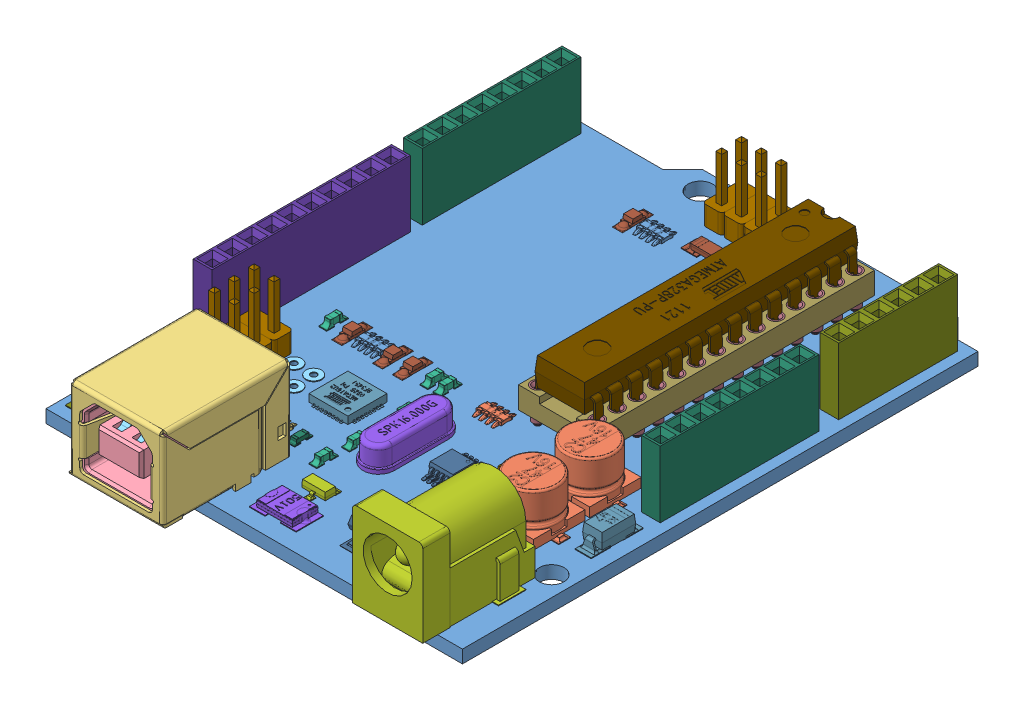
SolidWorks assembly arduino uno, configuration Default. Lengths in mm.
Overall size (53.34 15.25 74.97).
87 component instances, 35 part files, 133 mates.
Components (placement in the parent):
- unoboard blue-1: unoboard blue [Default] at origin size (53.34 1.65 68.58)
- 47uf CAP Dcase-1: 47uf CAP Dcase [Default] at (-9.4141 0 -18.4991) x (0 0 -1) z (1 0 0) size (6.6 5.81 8)
- USB type b-1: USB type b [Default] at (-38.02 0.43 6.35) size (14.34 15.2 16.54)
  - USB SHELL-1: USB SHELL [Default] at origin size (14.34 15.2 16.5)
  - USB core-1: USB core [Default] at origin size (11.3 10.68 15.75)
  - usb top contact-1: usb top contact [Default] at (1.25 6.09 -0.38) size (1 9.67 13.76)
  - usb btm contact-1: usb btm contact [Default] at (1.25 4.41 -0.38) size (1 6.84 11.76)
  - usb btm contact-2: usb btm contact [Default] at (-1.25 4.41 -0.38) size (1 6.84 11.76)
  - usb top contact-2: usb top contact [Default] at (-1.25 6.09 -0.38) size (1 9.67 13.76)
- power jack-1: power jack [Default] at (-7.675 0 1.905) size (11.2 15.2 15.9)
- 47uf CAP Dcase-2: 47uf CAP Dcase [Default] at (-9.4141 0 -25.7132) x (0 0 -1) z (1 0 0) size (6.6 5.81 8)
- crystal-1: crystal [Default] at (-26.162 0 -18.923) x (1 0 0) z (0 0 -1) size (4 5 11)
- 2pin_header__02-1: 2pin_header__02 [Default] at (-46.23 0 -15.75) size (5 11.75 2.54)
- nano - reg-1: nano - reg [Default] at (-17.399 0 -7.747) size (6.5 1.69 8.3)
- led-1: led [Default] at (-34.29 0 -27.94) x (0 0 1) z (-1 0 0) size (4 0.86 1.35)
- 2pin_header__02-2: 2pin_header__02 [Default] at (-30.43 0 -64.91) x (0 0 1) z (-1 0 0) size (5 11.75 2.54)
- dip28-1: dip28 [Default] at (-16.383 1.5 -46.355) x (0 0 -1) z (1 0 0) size (35.48 7.37 10.1)
  - dip28-1: dip28 [Default] at origin size (35.48 2.8 10.1)
  - dip socket pin-1: dip socket pin [Default] at (16.51 2.8 -3.81) size (1.7 7.37 1.7)
  - dip socket pin-2: dip socket pin [Default] at (16.51 2.8 3.81) size (1.7 7.37 1.7)
  - dip socket pin-3: dip socket pin [Default] at (13.97 2.8 -3.81) size (1.7 7.37 1.7)
  - dip socket pin-4: dip socket pin [Default] at (13.97 2.8 3.81) size (1.7 7.37 1.7)
  - dip socket pin-5: dip socket pin [Default] at (11.43 2.8 -3.81) size (1.7 7.37 1.7)
  - dip socket pin-6: dip socket pin [Default] at (11.43 2.8 3.81) size (1.7 7.37 1.7)
  - dip socket pin-7: dip socket pin [Default] at (8.89 2.8 -3.81) size (1.7 7.37 1.7)
  - dip socket pin-8: dip socket pin [Default] at (8.89 2.8 3.81) size (1.7 7.37 1.7)
  - dip socket pin-9: dip socket pin [Default] at (6.35 2.8 -3.81) size (1.7 7.37 1.7)
  - dip socket pin-10: dip socket pin [Default] at (6.35 2.8 3.81) size (1.7 7.37 1.7)
  - dip socket pin-11: dip socket pin [Default] at (3.81 2.8 -3.81) size (1.7 7.37 1.7)
  - dip socket pin-12: dip socket pin [Default] at (3.81 2.8 3.81) size (1.7 7.37 1.7)
  - dip socket pin-13: dip socket pin [Default] at (1.27 2.8 -3.81) size (1.7 7.37 1.7)
  - dip socket pin-14: dip socket pin [Default] at (1.27 2.8 3.81) size (1.7 7.37 1.7)
  - dip socket pin-15: dip socket pin [Default] at (-1.27 2.8 -3.81) size (1.7 7.37 1.7)
  - dip socket pin-16: dip socket pin [Default] at (-1.27 2.8 3.81) size (1.7 7.37 1.7)
  - dip socket pin-17: dip socket pin [Default] at (-3.81 2.8 -3.81) size (1.7 7.37 1.7)
  - dip socket pin-18: dip socket pin [Default] at (-3.81 2.8 3.81) size (1.7 7.37 1.7)
  - dip socket pin-19: dip socket pin [Default] at (-6.35 2.8 -3.81) size (1.7 7.37 1.7)
  - dip socket pin-20: dip socket pin [Default] at (-6.35 2.8 3.81) size (1.7 7.37 1.7)
  - dip socket pin-21: dip socket pin [Default] at (-8.89 2.8 -3.81) size (1.7 7.37 1.7)
  - dip socket pin-22: dip socket pin [Default] at (-8.89 2.8 3.81) size (1.7 7.37 1.7)
  - dip socket pin-23: dip socket pin [Default] at (-11.43 2.8 -3.81) size (1.7 7.37 1.7)
  - dip socket pin-24: dip socket pin [Default] at (-11.43 2.8 3.81) size (1.7 7.37 1.7)
  - dip socket pin-25: dip socket pin [Default] at (-13.97 2.8 -3.81) size (1.7 7.37 1.7)
  - dip socket pin-26: dip socket pin [Default] at (-13.97 2.8 3.81) size (1.7 7.37 1.7)
  - dip socket pin-27: dip socket pin [Default] at (-16.51 2.8 -3.81) size (1.7 7.37 1.7)
  - dip socket pin-28: dip socket pin [Default] at (-16.51 2.8 3.81) size (1.7 7.37 1.7)
- 2pin_header__02-3: 2pin_header__02 [Default] at (-27.89 0 -64.91) x (0 0 1) z (-1 0 0) size (5 11.75 2.54)
- 2pin_header__02-4: 2pin_header__02 [Default] at (-25.35 0 -64.91) x (0 0 1) z (-1 0 0) size (5 11.75 2.54)
- 2pin_header__02-5: 2pin_header__02 [Default] at (-46.23 0 -18.29) size (5 11.75 2.54)
- 2pin_header__02-6: 2pin_header__02 [Default] at (-46.23 0 -20.83) size (5 11.75 2.54)
- atmega16u2-1: atmega16u2 [Default] at (-34.671 0.06 -20) x (1 0 0) z (0 0 -1) size (5.5 1.01 5.5)
- led-2: led [Default] at (-36.83 0 -27.94) x (0 0 1) z (-1 0 0) size (4 0.86 1.35)
- led-3: led [Default] at (-42.037 0 -27.94) x (0 0 1) z (-1 0 0) size (4 0.86 1.35)
- led-4: led [Default] at (-36.576 0 -58.42) x (0 0 1) z (-1 0 0) size (4 0.86 1.35)
- 8 PORT HEADER-3: 8 PORT HEADER [Default] at (-50.8 0 -45.72) x (0 0 -1) z (1 0 0) size (20.32 10.51 2.41)
- 8 PORT HEADER-4: 8 PORT HEADER [Default] at (-2.54 0 -27.94) x (0 0 -1) z (1 0 0) size (20.32 10.51 2.41)
- 6 PORT HEADER-3: 6 PORT HEADER [Default] at (-2.54 0 -50.8) x (0 0 -1) z (1 0 0) size (15.24 10.51 2.41)
- 10 PORT HEADER-1: 10 PORT HEADER [Default] at (-50.8 0 -18.796) x (0 0 -1) z (1 0 0) size (25.4 10.51 2.41)
- ATMEL328P-1: ATMEL328P [Default] at (-16.383 4.3 -46.355) x (0 0 -1) z (1 0 0) size (35 7.27 7.87)
- 102 RESISTOR PACK-1: 102 RESISTOR PACK [Default] at (-33.782 0 -58.42) size (3.2 0.46 3)
- 102 RESISTOR PACK-2: 102 RESISTOR PACK [Default] at (-39.37 0 -27.94) size (3.2 0.46 3)
- 103 RESISTOR PACK-3: 103 RESISTOR PACK [Default] at (-23.876 0 -27.94) size (3.2 0.46 3)
- 220 RESISTOR PACK-1: 220 RESISTOR PACK [Default] at (-36.83 0 -12.827) size (3.2 0.46 3)
- 16mhz crystal - measured-1: 16mhz crystal - measured [Default] at (-24.892 0 -41.275) x (0 0 -1) z (1 0 0) size (3.4 0.8 2)
- PADS001-1: PADS001 [Default] at (-39.878 0.1 -18.288) x (-1 0 0) z (0 0 1) size (4.54 0.1 4.54)
- 603 cap on pad-1: 603 cap on pad [Default] at (-44.45 0 -27.94) x (0 0 -1) z (1 0 0) size (2.76 0.9 1.12)
- ssot3-1: ssot3 [Default] at (-26.5 0 -8.128) x (-1 0 0) z (0 0 -1) size (3 1.13 3.09)
- mf-msmf050-2-1: mf-msmf050-2 [Default] at (-26.5 0 -4.064) size (5.77 1.02 3.72)
- 603 cap on pad-2: 603 cap on pad [Default] at (-29.845 0 -27.94) x (0 0 -1) z (1 0 0) size (2.76 0.9 1.12)
- 603 cap on pad-3: 603 cap on pad [Default] at (-31.496 0 -27.94) x (0 0 -1) z (1 0 0) size (2.76 0.9 1.12)
- lmv358-1: lmv358 [Default] at (-15.24 0 -21.971) x (0 0 -1) z (1 0 0) size (3.7 1.4 2.9)
- 603 cap on pad-4: 603 cap on pad [Default] at (-15.24 0 -18.415) size (2.76 0.9 1.12)
- 603 cap on pad-5: 603 cap on pad [Default] at (-29.845 0 -12.065) x (0 0 1) z (-1 0 0) size (2.76 0.9 1.12)
- 603 cap on pad-6: 603 cap on pad [Default] at (-29.591 0 -22.352) x (0 0 1) z (-1 0 0) size (2.76 0.9 1.12)
- 603 cap on pad-7: 603 cap on pad [Default] at (-29.591 0 -16.002) x (0 0 1) z (-1 0 0) size (2.76 0.9 1.12)
- 603 cap on pad-8: 603 cap on pad [Default] at (-41.91 0 -12.7) x (0 0 1) z (-1 0 0) size (2.76 0.9 1.12)
- lp2985dgkr-1: lp2985dgkr [Default] at (-20.32 0 -19.05) x (0 0 -1) z (1 0 0) size (5.85 1.1 3)
- cd1206 diode-1: cd1206 diode [Default] at (-27.94 0 -59.436) x (0 0 -1) z (1 0 0) size (2.07 0.96 5)
- cd1206 diode-2: cd1206 diode [Default] at (-46.228 0 -13.081) x (0 0 1) z (-1 0 0) size (2.07 0.96 5)
- 603 resistor-1: 603 resistor [Default] at (-29.591 0 -19.05) x (0 0 1) z (-1 0 0) size (2.36 0.61 1.03)
- blm21-1: blm21 [Default] at (-45.085 0 -7.62) x (0 0 -1) z (1 0 0) size (2.76 0.95 1.32)
- m7 diode-1: m7 diode [Default] at (-2.794 0 -21.59) x (0 0 -1) z (1 0 0) size (6.66 2.35 2.5)
- MLC0603-1: MLC0603 [Default] at (-33.655 0 -12.827) x (0 0 -1) z (1 0 0) size (2.36 0.6 1.03)
- MLC0603-2: MLC0603 [Default] at (-39.37 0 -12.827) x (0 0 -1) z (1 0 0) size (2.36 0.6 1.03)
- RESET BUTTON-1: RESET BUTTON [Default] at (-49.403 0 -6.35) size (6.2 3.1 9.6)
  - RESET CORE-1: RESET CORE [Default] at (0 0.1 0) x (-1 0 0) z (0 0 -1) size (6.2 3.1 9.6)
  - RESET-1: RESET [Default] at (0 0.1 0) x (0 0 1) z (-1 0 0) size (7.3 2 6.2)
Mates (geometry in assembly coordinates):
- Distance1: distance = 1.905 mm aligned: plane of power jack-1 through (-7.675 0 1.905) normal (0 0 1); plane of unoboard blue-1 through (0 0 0) normal (0 0 1)
- Coincident2: coincident aligned: plane of unoboard blue-1 through (0 0 0) normal (0 1 0); plane of power jack-1 through (-7.675 0 1.905) normal (0 1 0)
- Coincident3: coincident anti-aligned: plane of unoboard blue-1 through (0 0 0) normal (0 1 0); plane of USB type b-1/USB core-1 through (-38.02 0 6.35) normal (0 -1 0)
- Distance2: distance = 6.35 mm aligned: plane of USB type b-1/USB SHELL-1 through (-38.02 0.43 6.35) normal (0 0 1); plane of unoboard blue-1 through (0 0 0) normal (0 0 1)
- Coincident5: coincident aligned: plane of unoboard blue-1 through (0 0 0) normal (0 1 0); plane of 47uf CAP Dcase-1 through (-9.4141 0 -18.4991) normal (0 1 0)
- Parallel1: parallel anti-aligned: plane of unoboard blue-1 through (0 0 0) normal (0 0 1); plane of 47uf CAP Dcase-1 through (-9.4141 0 -18.4991) normal (0 0 -1)
- Coincident7: coincident aligned: plane of 47uf CAP Dcase-1 through (-6.1141 1.5 -15.1991) normal (1 0 0); plane of 47uf CAP Dcase-2 through (-6.1141 1.5 -22.4132) normal (1 0 0)
- Coincident8: coincident anti-aligned: plane of unoboard blue-1 through (0 0 0) normal (0 1 0); plane of 47uf CAP Dcase-2 through (-8.1891 0 -25.7132) normal (0 -1 0)
- Distance3: distance = 3.175 mm aligned: plane of power jack-1 through (-3.175 10.5 -1.595) normal (1 0 0); plane of unoboard blue-1 through (0 -1.65 0) normal (1 0 0)
- Distance4: distance = 32 mm aligned: plane of USB type b-1/USB SHELL-1 through (-32 0.43 6.35) normal (1 0 0); plane of unoboard blue-1 through (0 -1.65 0) normal (1 0 0)
- Coincident11: coincident anti-aligned: plane of unoboard blue-1 through (0 0 0) normal (0 1 0); plane of crystal-1 through (-26.162 0 -22.423) normal (0 -1 0)
- Concentric1: concentric aligned: cylinder of unoboard blue-1 through (-26.162 -10 -16.383) axis (0 1 0) radius 0.5; cylinder of crystal-1 through (-26.162 -2 -16.383) axis (0 1 0) radius 0.4
- Concentric2: concentric aligned: cylinder of unoboard blue-1 through (-26.162 -10 -21.463) axis (0 1 0) radius 0.5; cylinder of crystal-1 through (-26.162 -2 -21.463) axis (0 1 0) radius 0.4
- Coincident12: coincident anti-aligned: plane of unoboard blue-1 through (0 0 0) normal (0 1 0); plane of 2pin_header__02-1 through (-44.23 0 -14.98) normal (0 -1 0)
- Distance5: distance = 15.75 mm aligned: plane of 2pin_header__02-1 through (-46.23 0 -15.75) normal (0 0 1); plane of assembly through (0 0 0) normal (0 0 1)
- Distance6: distance = 46.23 mm aligned: plane of 2pin_header__02-1 through (-46.23 0 -15.75) normal (1 0 0); plane of assembly through (0 0 0) normal (1 0 0)
- Coincident15: coincident anti-aligned: plane of unoboard blue-1 through (0 0 0) normal (0 1 0); plane of 2pin_header__02-2 through (-31.2 0 -62.91) normal (0 -1 0)
- Distance7: distance = 64.91 mm aligned: plane of 2pin_header__02-2 through (-30.43 0 -64.91) normal (0 0 1); plane of assembly through (0 0 0) normal (0 0 1)
- Distance8: distance = 30.43 mm anti-aligned: plane of 2pin_header__02-2 through (-30.43 0 -64.91) normal (-1 0 0); plane of assembly through (0 0 0) normal (1 0 0)
- Coincident19: coincident anti-aligned: plane of unoboard blue-1 through (0 0 0) normal (0 1 0); plane of nano - reg-1 through (-17.399 0 -7.747) normal (0 -1 0)
- Concentric3: concentric aligned: cylinder of unoboard blue-1 through (-20.193 -10 -62.865) axis (0 1 0) radius 0.4; cylinder of dip28-1/dip socket pin-1 through (-20.193 33.2926 -62.865) axis (0 1 0) radius 0.25
- Concentric4: concentric aligned: cylinder of unoboard blue-1 through (-12.573 -10 -29.845) axis (0 1 0) radius 0.4; cylinder of dip28-1/dip socket pin-28 through (-12.573 33.2926 -29.845) axis (0 1 0) radius 0.25
- Distance9: distance = 1.5 mm anti-aligned: plane of dip28-1/dip28-1 through (-11.333 1.5 -64.095) normal (0 -1 0); plane of unoboard blue-1 through (0 0 0) normal (0 1 0)
- Coincident21: coincident anti-aligned: plane of unoboard blue-1 through (0 0 0) normal (0 1 0); plane of atmega16u2-1 through (-34.671 0 -20) normal (0 -1 0)
- Distance10: distance = 20 mm anti-aligned: plane of atmega16u2-1 through (-34.671 0.06 -20) normal (0 0 -1); plane of unoboard blue-1 through (0 0 0) normal (0 0 1)
- Distance11: distance = 34.671 mm aligned: plane of atmega16u2-1 through (-34.671 0.06 -20) normal (1 0 0); plane of unoboard blue-1 through (0 0 0) normal (1 0 0)
- Coincident25: coincident anti-aligned: plane of unoboard blue-1 through (0 0 0) normal (0 1 0); plane of led-1 through (-34.29 0 -28.94) normal (0 -1 0)
- Distance12: distance = 34.29 mm anti-aligned: plane of led-1 through (-34.29 0 -27.94) normal (-1 0 0); plane of unoboard blue-1 through (0 0 0) normal (1 0 0)
- Distance13: distance = 27.94 mm aligned: plane of led-1 through (-34.29 0 -27.94) normal (0 0 1); plane of unoboard blue-1 through (0 0 0) normal (0 0 1)
- Coincident28: coincident aligned: plane of led-2 through (-36.83 0 -28.94) normal (0 -1 0); plane of led-3 through (-42.037 0 -28.94) normal (0 -1 0)
- Coincident29: coincident aligned: plane of led-1 through (-34.29 0 -27.94) normal (0 0 1); plane of led-2 through (-36.83 0 -27.94) normal (0 0 1)
- Coincident30: coincident aligned: plane of led-1 through (-34.29 0 -27.94) normal (0 0 1); plane of led-3 through (-42.037 0 -27.94) normal (0 0 1)
- Distance14: distance = 2.54 mm aligned: plane of led-2 through (-36.83 0 -27.94) normal (-1 0 0); plane of led-1 through (-34.29 0 -27.94) normal (-1 0 0)
- Coincident32: coincident anti-aligned: plane of unoboard blue-1 through (0 0 0) normal (0 1 0); plane of led-2 through (-36.83 0 -28.94) normal (0 -1 0)
- Distance15: distance = 42.037 mm anti-aligned: plane of led-3 through (-42.037 0 -27.94) normal (-1 0 0); plane of unoboard blue-1 through (0 0 0) normal (1 0 0)
- Coincident34: coincident anti-aligned: plane of unoboard blue-1 through (0 0 0) normal (0 1 0); plane of led-4 through (-36.576 0 -59.42) normal (0 -1 0)
- Distance16: distance = 36.576 mm anti-aligned: plane of led-4 through (-36.576 0 -58.42) normal (-1 0 0); plane of unoboard blue-1 through (0 0 0) normal (1 0 0)
- Distance17: distance = 58.42 mm aligned: plane of led-4 through (-36.576 0 -58.42) normal (0 0 1); plane of unoboard blue-1 through (0 0 0) normal (0 0 1)
- Coincident37: coincident aligned: plane of unoboard blue-1 through (0 0 0) normal (0 1 0); plane of 8 PORT HEADER-4 through (-2.54 0 -27.94) normal (0 1 0)
- Coincident38: coincident aligned: plane of unoboard blue-1 through (0 0 0) normal (0 1 0); plane of 8 PORT HEADER-3 through (-50.8 0 -45.72) normal (0 1 0)
- Parallel2: parallel aligned: plane of unoboard blue-1 through (0 0 0) normal (1 0 0); plane of 8 PORT HEADER-4 through (-2.54 0 -27.94) normal (1 0 0)
- Parallel3: parallel aligned: plane of unoboard blue-1 through (0 0 0) normal (1 0 0); plane of 8 PORT HEADER-3 through (-50.8 0 -45.72) normal (1 0 0)
- Concentric5: concentric aligned: cylinder of unoboard blue-1 through (-2.54 -1.65 -27.94) axis (0 1 0) radius 0.4; line of 8 PORT HEADER-4 through (-2.54 -2.5255 -27.94) axis (0 1 0)
- Concentric6: concentric aligned: cylinder of unoboard blue-1 through (-50.8 -1.65 -45.72) axis (0 1 0) radius 0.4; line of 8 PORT HEADER-3 through (-50.8 -2.5255 -45.72) axis (0 1 0)
- Coincident43: coincident aligned: plane of unoboard blue-1 through (0 0 0) normal (0 1 0); plane of 10 PORT HEADER-1 through (-50.8 0 -18.796) normal (0 1 0)
- Coincident44: coincident aligned: plane of unoboard blue-1 through (0 0 0) normal (0 1 0); plane of 6 PORT HEADER-3 through (-2.54 0 -50.8) normal (0 1 0)
- Parallel4: parallel aligned: plane of unoboard blue-1 through (0 0 0) normal (1 0 0); plane of 6 PORT HEADER-3 through (-2.54 0 -50.8) normal (1 0 0)
- Parallel5: parallel aligned: plane of unoboard blue-1 through (0 0 0) normal (1 0 0); plane of 10 PORT HEADER-1 through (-50.8 0 -18.796) normal (1 0 0)
- Concentric7: concentric aligned: cylinder of unoboard blue-1 through (-50.8 -1.65 -18.796) axis (0 1 0) radius 0.4; line of 10 PORT HEADER-1 through (-50.8 -2.5255 -18.796) axis (0 1 0)
- Concentric9: concentric aligned: cylinder of unoboard blue-1 through (-2.54 -1.65 -50.8) axis (0 1 0) radius 0.4; line of 6 PORT HEADER-3 through (-2.54 -2.5255 -50.8) axis (0 1 0)
- Coincident50: coincident aligned: plane of dip28-1/dip28-1 through (-16.383 1.5 -46.355) normal (0 0 -1); plane of ATMEL328P-1 through (-16.383 4.3 -46.355) normal (0 0 -1)
- Coincident51: coincident aligned: plane of dip28-1 through (-16.383 1.5 -46.355) normal (1 0 0); plane of ATMEL328P-1 through (-16.383 4.3 -46.355) normal (1 0 0)
- Coincident52: coincident aligned: plane of dip28-1/dip28-1 through (-11.333 4.3 -64.095) normal (0 1 0); plane of ATMEL328P-1 through (-16.383 4.3 -46.355) normal (0 1 0)
- Distance18: distance = 7.747 mm: plane of nano - reg-1 through (-17.399 0 -7.747) normal (0 0 1); line of unoboard blue-1 through (0 53.34 -53.34) axis (0 0 1)
- Distance19: distance = 17.399 mm aligned: plane of nano - reg-1 through (-17.399 0 -7.747) normal (1 0 0); plane of unoboard blue-1 through (0 0 0) normal (1 0 0)
- Coincident55: coincident anti-aligned: plane of unoboard blue-1 through (0 0 0) normal (0 1 0); plane of 102 RESISTOR PACK-1 through (-33.982 0 -59.12) normal (0 -1 0)
- Distance20: distance = 33.782 mm aligned: plane of 102 RESISTOR PACK-1 through (-33.782 0 -58.42) normal (1 0 0); plane of unoboard blue-1 through (0 0 0) normal (1 0 0)
- Distance21: distance = 58.42 mm aligned: plane of 102 RESISTOR PACK-1 through (-33.782 0 -58.42) normal (0 0 1); plane of unoboard blue-1 through (0 0 0) normal (0 0 1)
- Coincident58: coincident aligned: plane of 102 RESISTOR PACK-2 through (-39.37 0 -27.94) normal (0 1 0); plane of 103 RESISTOR PACK-3 through (-23.876 0 -27.94) normal (0 1 0)
- Coincident59: coincident aligned: plane of unoboard blue-1 through (0 0 0) normal (0 1 0); plane of 103 RESISTOR PACK-3 through (-23.876 0 -27.94) normal (0 1 0)
- Coincident60: coincident aligned: plane of 102 RESISTOR PACK-2 through (-39.37 0 -27.94) normal (0 0 1); plane of 103 RESISTOR PACK-3 through (-23.876 0 -27.94) normal (0 0 1)
- Distance22: distance = 23.876 mm aligned: plane of 103 RESISTOR PACK-3 through (-23.876 0 -27.94) normal (1 0 0); plane of unoboard blue-1 through (0 0 0) normal (1 0 0)
- Distance23: distance = 39.37 mm aligned: plane of 102 RESISTOR PACK-2 through (-39.37 0 -27.94) normal (1 0 0); plane of unoboard blue-1 through (0 0 0) normal (1 0 0)
- Distance24: distance = 27.94 mm aligned: plane of 102 RESISTOR PACK-2 through (-39.37 0 -27.94) normal (0 0 1); plane of unoboard blue-1 through (0 0 0) normal (0 0 1)
- Distance25: distance = 12.827 mm aligned: plane of 220 RESISTOR PACK-1 through (-36.83 0 -12.827) normal (0 0 1); plane of unoboard blue-1 through (0 0 0) normal (0 0 1)
- Distance26: distance = 36.83 mm aligned: plane of 220 RESISTOR PACK-1 through (-36.83 0 -12.827) normal (1 0 0); plane of unoboard blue-1 through (0 0 0) normal (1 0 0)
- Coincident66: coincident aligned: plane of unoboard blue-1 through (0 0 0) normal (0 1 0); plane of 220 RESISTOR PACK-1 through (-36.83 0 -12.827) normal (0 1 0)
- Coincident67: coincident anti-aligned: plane of unoboard blue-1 through (0 0 0) normal (0 1 0); plane of 16mhz crystal - measured-1 through (-24.892 0 -41.275) normal (0 -1 0)
- Distance27: distance = 41.275 mm anti-aligned: plane of 16mhz crystal - measured-1 through (-24.892 0 -41.275) normal (0 0 -1); plane of unoboard blue-1 through (0 0 0) normal (0 0 1)
- Distance28: distance = 24.892 mm aligned: plane of 16mhz crystal - measured-1 through (-24.892 0 -41.275) normal (1 0 0); plane of unoboard blue-1 through (0 0 0) normal (1 0 0)
- Coincident70: coincident anti-aligned: plane of unoboard blue-1 through (0 0 0) normal (0 1 0); plane of PADS001-1 through (-42.418 0 -18.288) normal (0 -1 0)
- Distance29: distance = 18.288 mm aligned: plane of PADS001-1 through (-39.878 0.1 -18.288) normal (0 0 1); plane of unoboard blue-1 through (0 0 0) normal (0 0 1)
- Distance30: distance = 39.878 mm anti-aligned: plane of PADS001-1 through (-39.878 0.1 -18.288) normal (-1 0 0); plane of unoboard blue-1 through (0 0 0) normal (1 0 0)
- Distance31: distance = 4.064 mm aligned: plane of mf-msmf050-2-1 through (-26.5 0 -4.064) normal (0 0 1); plane of unoboard blue-1 through (0 0 0) normal (0 0 1)
- Distance32: distance = 26.5 mm aligned: plane of mf-msmf050-2-1 through (-26.5 0 -4.064) normal (1 0 0); plane of unoboard blue-1 through (0 0 0) normal (1 0 0)
- Coincident72: coincident aligned: plane of unoboard blue-1 through (0 0 0) normal (0 1 0); plane of mf-msmf050-2-1 through (-26.5 0 -4.064) normal (0 1 0)
- Distance33: distance = 8.128 mm anti-aligned: plane of unoboard blue-1 through (0 0 0) normal (0 0 1); plane of ssot3-1 through (-26.5 0 -8.128) normal (0 0 -1)
- Coincident74: coincident anti-aligned: plane of ssot3-1 through (-26.5 0 -8.128) normal (-1 0 0); plane of mf-msmf050-2-1 through (-26.5 0 -4.064) normal (1 0 0)
- Coincident75: coincident aligned: plane of unoboard blue-1 through (0 0 0) normal (0 1 0); plane of ssot3-1 through (-26.5 0 -8.128) normal (0 1 0)
- Coincident76: coincident anti-aligned: plane of led-1 through (-34.29 0 -27.94) normal (0 0 1); plane of 603 cap on pad-1 through (-44.45 0 -27.94) normal (0 0 -1)
- Coincident77: coincident aligned: plane of unoboard blue-1 through (0 0 0) normal (0 1 0); plane of 603 cap on pad-1 through (-44.45 0 -27.94) normal (0 1 0)
- Distance34: distance = 44.45 mm aligned: plane of 603 cap on pad-1 through (-44.45 0 -27.94) normal (1 0 0); plane of unoboard blue-1 through (0 0 0) normal (1 0 0)
- Coincident79: coincident aligned: plane of 603 cap on pad-2 through (-29.845 0 -27.94) normal (0 1 0); plane of 603 cap on pad-3 through (-31.496 0 -27.94) normal (0 1 0)
- Coincident80: coincident aligned: plane of 603 cap on pad-2 through (-29.845 0 -27.94) normal (0 0 -1); plane of 603 cap on pad-3 through (-31.496 0 -27.94) normal (0 0 -1)
- Coincident81: coincident aligned: plane of unoboard blue-1 through (0 0 0) normal (0 1 0); plane of 603 cap on pad-2 through (-29.845 0 -27.94) normal (0 1 0)
- Coincident82: coincident aligned: plane of 603 cap on pad-1 through (-44.45 0 -27.94) normal (0 0 -1); plane of 603 cap on pad-2 through (-29.845 0 -27.94) normal (0 0 -1)
- Distance36: distance = 29.845 mm aligned: plane of 603 cap on pad-2 through (-29.845 0 -27.94) normal (1 0 0); plane of unoboard blue-1 through (0 0 0) normal (1 0 0)
- Distance37: distance = 31.496 mm aligned: plane of 603 cap on pad-3 through (-31.496 0 -27.94) normal (1 0 0); plane of unoboard blue-1 through (0 0 0) normal (1 0 0)
- Distance38: distance = 15.24 mm aligned: plane of unoboard blue-1 through (0 0 0) normal (1 0 0); plane of lmv358-1 through (-15.24 0 -21.971) normal (1 0 0)
- Distance39: distance = 21.971 mm anti-aligned: plane of lmv358-1 through (-15.24 0 -21.971) normal (0 0 -1); plane of unoboard blue-1 through (0 0 0) normal (0 0 1)
- Coincident88: coincident aligned: plane of unoboard blue-1 through (0 0 0) normal (0 1 0); plane of lmv358-1 through (-15.24 0 -21.971) normal (0 1 0)
- Distance40: distance = 18.415 mm aligned: plane of 603 cap on pad-4 through (-15.24 0 -18.415) normal (0 0 1); plane of unoboard blue-1 through (0 0 0) normal (0 0 1)
- Distance41: distance = 15.24 mm aligned: plane of 603 cap on pad-4 through (-15.24 0 -18.415) normal (1 0 0); plane of unoboard blue-1 through (0 0 0) normal (1 0 0)
- Coincident91: coincident aligned: plane of unoboard blue-1 through (0 0 0) normal (0 1 0); plane of 603 cap on pad-4 through (-15.24 0 -18.415) normal (0 1 0)
- Coincident92: coincident aligned: plane of unoboard blue-1 through (0 0 0) normal (0 1 0); plane of 603 cap on pad-7 through (-29.591 0 -16.002) normal (0 1 0)
- Coincident93: coincident aligned: plane of unoboard blue-1 through (0 0 0) normal (0 1 0); plane of 603 cap on pad-6 through (-29.591 0 -22.352) normal (0 1 0)
- Coincident94: coincident aligned: plane of 603 cap on pad-5 through (-29.845 0 -12.065) normal (0 1 0); plane of unoboard blue-1 through (0 0 0) normal (0 1 0)
- Coincident95: coincident aligned: plane of 603 cap on pad-8 through (-41.91 0 -12.7) normal (0 1 0); plane of unoboard blue-1 through (0 0 0) normal (0 1 0)
- Coincident96: coincident aligned: plane of 603 cap on pad-7 through (-29.591 0 -16.002) normal (-1 0 0); plane of 603 cap on pad-6 through (-29.591 0 -22.352) normal (-1 0 0)
- Distance42: distance = 29.591 mm anti-aligned: plane of 603 cap on pad-7 through (-29.591 0 -16.002) normal (-1 0 0); plane of unoboard blue-1 through (0 0 0) normal (1 0 0)
- Distance43: distance = 22.352 mm: plane of 603 cap on pad-6 through (-29.591 0 -22.352) normal (0 0 1); line of unoboard blue-1 through (0 53.34 -53.34) axis (0 0 1)
- Distance44: distance = 16.002 mm aligned: plane of 603 cap on pad-7 through (-29.591 0 -16.002) normal (0 0 1); plane of unoboard blue-1 through (0 0 0) normal (0 0 1)
- Distance45: distance = 29.845 mm anti-aligned: plane of 603 cap on pad-5 through (-29.845 0 -12.065) normal (-1 0 0); plane of unoboard blue-1 through (0 0 0) normal (1 0 0)
- Distance46: distance = 12.065 mm aligned: plane of 603 cap on pad-5 through (-29.845 0 -12.065) normal (0 0 1); plane of unoboard blue-1 through (0 0 0) normal (0 0 1)
- Distance47: distance = 41.91 mm anti-aligned: plane of 603 cap on pad-8 through (-41.91 0 -12.7) normal (-1 0 0); plane of unoboard blue-1 through (0 0 0) normal (1 0 0)
- Distance48: distance = 12.7 mm aligned: plane of 603 cap on pad-8 through (-41.91 0 -12.7) normal (0 0 1); plane of unoboard blue-1 through (0 0 0) normal (0 0 1)
- Distance49: distance = 20.32 mm aligned: plane of lp2985dgkr-1 through (-20.32 0 -19.05) normal (1 0 0); plane of unoboard blue-1 through (0 0 0) normal (1 0 0)
- Distance50: distance = 19.05 mm anti-aligned: plane of lp2985dgkr-1 through (-20.32 0 -19.05) normal (0 0 -1); plane of unoboard blue-1 through (0 0 0) normal (0 0 1)
- Coincident99: coincident aligned: plane of unoboard blue-1 through (0 0 0) normal (0 1 0); plane of lp2985dgkr-1 through (-20.32 0 -19.05) normal (0 1 0)
- Distance51: distance = 27.94 mm aligned: plane of cd1206 diode-1 through (-27.94 0 -59.436) normal (1 0 0); plane of unoboard blue-1 through (0 0 0) normal (1 0 0)
- Distance52: distance = 59.436 mm anti-aligned: plane of cd1206 diode-1 through (-27.94 0 -59.436) normal (0 0 -1); plane of unoboard blue-1 through (0 0 0) normal (0 0 1)
- Coincident102: coincident aligned: plane of unoboard blue-1 through (0 0 0) normal (0 1 0); plane of cd1206 diode-1 through (-27.94 0 -59.436) normal (0 1 0)
- Distance53: distance = 46.228 mm anti-aligned: plane of cd1206 diode-2 through (-46.228 0 -13.081) normal (-1 0 0); plane of unoboard blue-1 through (0 0 0) normal (1 0 0)
- Distance54: distance = 13.081 mm aligned: plane of unoboard blue-1 through (0 0 0) normal (0 0 1); plane of cd1206 diode-2 through (-46.228 0 -13.081) normal (0 0 1)
- Coincident105: coincident aligned: plane of unoboard blue-1 through (0 0 0) normal (0 1 0); plane of cd1206 diode-2 through (-46.228 0 -13.081) normal (0 1 0)
- Distance55: distance = 29.591 mm anti-aligned: plane of 603 resistor-1 through (-29.591 0 -19.05) normal (-1 0 0); plane of unoboard blue-1 through (0 0 0) normal (1 0 0)
- Distance56: distance = 19.05 mm aligned: plane of 603 resistor-1 through (-29.591 0 -19.05) normal (0 0 1); plane of unoboard blue-1 through (0 0 0) normal (0 0 1)
- Coincident108: coincident aligned: plane of unoboard blue-1 through (0 0 0) normal (0 1 0); plane of 603 resistor-1 through (-29.591 0 -19.05) normal (0 1 0)
- Distance57: distance = 7.62 mm anti-aligned: plane of blm21-1 through (-45.085 0 -7.62) normal (0 0 -1); plane of unoboard blue-1 through (0 0 0) normal (0 0 1)
- Distance58: distance = 45.085 mm aligned: plane of blm21-1 through (-45.085 0 -7.62) normal (1 0 0); plane of unoboard blue-1 through (0 0 0) normal (1 0 0)
- Distance59: distance = 21.59 mm anti-aligned: plane of m7 diode-1 through (-2.794 0 -21.59) normal (0 0 -1); plane of unoboard blue-1 through (0 0 0) normal (0 0 1)
- Distance60: distance = 2.794 mm aligned: plane of m7 diode-1 through (-2.794 0 -21.59) normal (1 0 0); plane of unoboard blue-1 through (0 0 0) normal (1 0 0)
- Coincident113: coincident aligned: plane of unoboard blue-1 through (0 0 0) normal (0 1 0); plane of m7 diode-1 through (-2.794 0 -21.59) normal (0 1 0)
- Coincident114: coincident anti-aligned: plane of 220 RESISTOR PACK-1 through (-36.83 0 -12.827) normal (0 0 1); plane of MLC0603-1 through (-33.655 0 -12.827) normal (0 0 -1)
- Distance61: distance = 33.655 mm aligned: plane of MLC0603-1 through (-33.655 0 -12.827) normal (1 0 0); plane of unoboard blue-1 through (0 0 0) normal (1 0 0)
- Coincident115: coincident aligned: plane of unoboard blue-1 through (0 0 0) normal (0 1 0); plane of MLC0603-1 through (-33.655 0 -12.827) normal (0 1 0)
- Coincident116: coincident aligned: plane of unoboard blue-1 through (0 0 0) normal (0 1 0); plane of blm21-1 through (-45.085 0 -7.62) normal (0 1 0)
- Coincident117: coincident anti-aligned: plane of 220 RESISTOR PACK-1 through (-36.83 0 -12.827) normal (0 0 1); plane of MLC0603-2 through (-39.37 0 -12.827) normal (0 0 -1)
- Coincident118: coincident aligned: plane of unoboard blue-1 through (0 0 0) normal (0 1 0); plane of MLC0603-2 through (-39.37 0 -12.827) normal (0 1 0)
- Distance62: distance = 39.37 mm aligned: plane of MLC0603-2 through (-39.37 0 -12.827) normal (1 0 0); plane of unoboard blue-1 through (0 0 0) normal (1 0 0)
- Distance63: distance = 49.403 mm aligned: plane of RESET BUTTON-1 through (-49.403 0 -6.35) normal (1 0 0); plane of unoboard blue-1 through (0 0 0) normal (1 0 0)
- Distance64: distance = 6.35 mm aligned: plane of RESET BUTTON-1; plane of unoboard blue-1 through (0 0 0) normal (0 0 1)
- Coincident122: coincident aligned: plane of unoboard blue-1 through (0 0 0) normal (0 1 0); plane of RESET BUTTON-1 through (-49.403 0 -6.35) normal (0 1 0)
